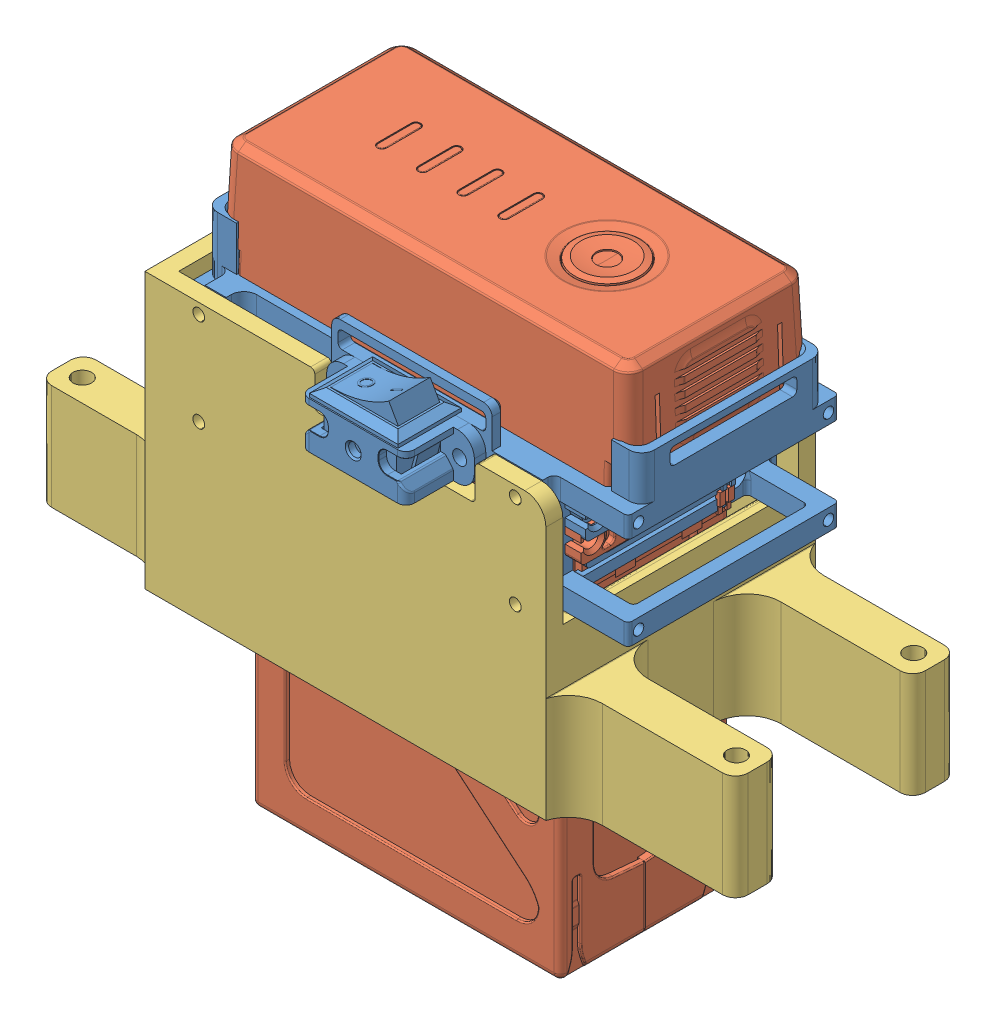
SolidWorks assembly 电池装配体, configuration 默认. Lengths in mm.
Overall size (165 134.81 73.55).
3 component instances, 3 part files, 7 mates.
Components (placement in the parent):
- TB电池架-1: TB电池架 [默认] at (-50.6927 1.7895 96.5476) size (103.5 37.5 69.3)
- TB电池-1: TB电池 [默认] at (-51.7927 -3.6105 96.5476) size (101.5 134.81 45.5)
- 电池支架-打印件-1: 电池支架-打印件 [默认] at (-4.6927 -29.2105 96.5476) x (0 0 -1) z (0 1 0) size (63.9 165 65.2)
Mates (geometry in assembly coordinates):
- 重合4: coincident anti-aligned: plane of TB电池架-1 through (-47.6927 -27.9117 121.1488) normal (1 0 0); plane of 电池-1 through (-47.6927 -107.4105 96.1476) normal (-1 0 0)
- 重合5: coincident anti-aligned: plane of TB电池架-1 through (-56.4939 -27.9117 76.0476) normal (0 0 1); plane of 电池-1 through (-11.0927 -50.4105 76.0476) normal (0 0 -1)
- 重合8: coincident anti-aligned: plane of TB电池架-1 through (-59.7939 1.7895 64.7464) normal (0 1 0); plane of 电池-1 through (-5.3927 1.7895 96.1476) normal (0 -1 0)
- 重合9: coincident anti-aligned: plane of TB电池架-1 through (-59.2939 -25.2105 68.3464) normal (0 -1 0); plane of 电池支架-打印件-1 through (-4.6927 -25.2105 96.5476) normal (0 1 0)
- 平行1: parallel aligned: plane of 电池-1 through (22.9073 0.3895 114.6476) normal (0 0 1); plane of 电池支架-打印件-1 through (51.3073 1.7895 128.4976) normal (0 0 1)
- 同心1: concentric anti-aligned: circle of BT电池架-1; circle of 电池支架-打印件-1
- 重合12: coincident anti-aligned: plane of TB电池架-1 through (-56.6927 -11.7105 96.5476) normal (-1 0 0); plane of 电池支架-打印件-1 through (-56.6927 1.7895 64.5976) normal (1 0 0)
